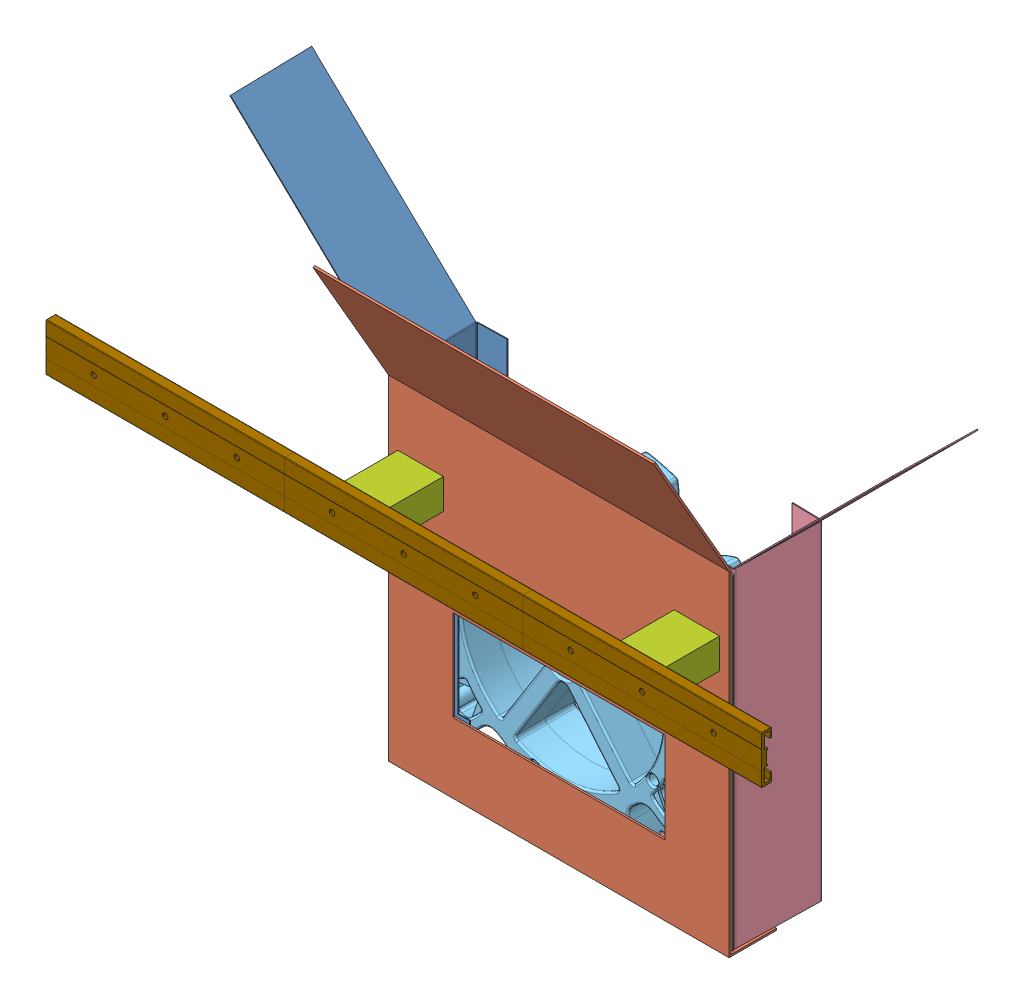
SolidWorks assembly Main Gear Asm, configuration Default. Lengths in mm.
Overall size (649.76 468.3 140.7).
37 component instances, 9 part files, 45 mates.
Components (placement in the parent):
- Right Side Gear Clamp-1: Right Side Gear Clamp [Default] at (-285.149 4.7752 -4.5915) x (-0.022934 0 -0.999737) z (0.999737 0 -0.022934) size (72.59 411.06 198.02)
- gear support back plate-1: gear support back plate [Default] at (0 1.6002 -1.6002) x (0 0 1) z (-1 0 0) size (102.99 390.99 285.75)
- Piano Hinge-1: Piano Hinge [Default] at (-286.5459 277.8252 -3.1875) x (0 -1 0) z (-0.999737 0 0.022934) size (273.05 1.59 10.45)
- Piano Hinge-2: Piano Hinge [Default] at (-286.5277 4.7752 -1.6002) x (0 1 0) z (-1 0 0) size (273.05 1.59 10.45)
- Piano Hinge-3: Piano Hinge [Default] at (0.7937 277.8252 -1.6002) x (0 -1 0) z (1 0 0) size (273.05 1.59 10.45)
- Piano Hinge-4: Piano Hinge [Default] at (0.81 4.7752 -3.1875) x (0 1 0) z (0.999791 0 0.020427) size (273.05 1.59 10.45)
- Left Side Gear Clamp-2: Left Side Gear Clamp [Default] at (0.8607 4.7752 -4.7362) x (0.020427 0 -0.999791) z (0.999791 0 0.020427) size (72.95 411.63 198.2)
- Gear Gampiece-1: Gear Gampiece [Default] at (-146.05 139.7 -30.6969) x (0.847389 -0.530972 0) z (0 0 1) size (282.2 275.37 50.81)
  - ip-3302 10T gear-1: ip-3302 10T gear [Default] at origin size (280.29 273.41 28.58)
  - ip-3302 10T gear-2: ip-3302 10T gear [Default] x (-0.999975 0.007024 0) z (0 0 -1) size (280.29 273.41 28.58)
  - am-1291 screw_90190A196-1: am-1291 screw_90190A196 [Default] at (-90.6774 0.3185 -5.969) x (-0.923728 -0.383049 0) z (0 0 -1) size (8.18 8.18 18.8)
  - am-1291 screw_90190A196-2: am-1291 screw_90190A196 [Default] at (-102.4824 75.0091 -4.3538) x (-0.923728 -0.383049 0) z (0 0 -1) size (8.18 8.18 18.8)
  - am-1291 screw_90190A196-3: am-1291 screw_90190A196 [Default] at (-126.9992 0.446 4.3538) size (8.18 8.18 18.8)
  - am-1291 screw_90190A196-4: am-1291 screw_90190A196 [Default] at (-73.1724 53.5565 5.969) size (8.18 8.18 18.8)
  - am-1291 screw_90190A196-5: am-1291 screw_90190A196 [Default] at (-27.718 86.3378 -5.969) x (-0.649749 0.760149 0) z (0 0 -1) size (8.18 8.18 18.8)
  - am-1291 screw_90190A196-6: am-1291 screw_90190A196 [Default] at (73.5468 53.0412 -5.969) x (0.522161 0.852847 0) z (0 0 -1) size (8.18 8.18 18.8)
  - am-1291 screw_90190A196-7: am-1291 screw_90190A196 [Default] at (73.1724 -53.5565 -5.969) x (0.972462 -0.233061 0) z (0 0 -1) size (8.18 8.18 18.8)
  - am-1291 screw_90190A196-8: am-1291 screw_90190A196 [Default] at (-28.3237 -86.141 -5.969) x (0.078854 -0.996886 0) z (0 0 -1) size (8.18 8.18 18.8)
  - am-1291 screw_90190A196-9: am-1291 screw_90190A196 [Default] at (39.6691 120.6456 -4.3538) x (-0.649749 0.760149 0) z (0 0 -1) size (8.18 8.18 18.8)
  - am-1291 screw_90190A196-10: am-1291 screw_90190A196 [Default] at (126.9992 -0.446 -4.3538) x (0.522161 0.852847 0) z (0 0 -1) size (8.18 8.18 18.8)
  - am-1291 screw_90190A196-11: am-1291 screw_90190A196 [Default] at (38.8207 -120.9213 -4.3538) x (0.972462 -0.233061 0) z (0 0 -1) size (8.18 8.18 18.8)
  - am-1291 screw_90190A196-12: am-1291 screw_90190A196 [Default] at (-103.0067 -74.2874 -4.3538) x (0.078854 -0.996886 0) z (0 0 -1) size (8.18 8.18 18.8)
  - am-1291 screw_90190A196-13: am-1291 screw_90190A196 [Default] at (-38.8207 120.9213 4.3538) x (0.309017 -0.951057 0) z (0 0 1) size (8.18 8.18 18.8)
  - am-1291 screw_90190A196-14: am-1291 screw_90190A196 [Default] at (103.0067 74.2874 4.3538) x (-0.809017 -0.587785 0) z (0 0 1) size (8.18 8.18 18.8)
  - am-1291 screw_90190A196-15: am-1291 screw_90190A196 [Default] at (102.4824 -75.0091 4.3538) x (-0.809017 0.587785 0) z (0 0 1) size (8.18 8.18 18.8)
  - am-1291 screw_90190A196-16: am-1291 screw_90190A196 [Default] at (-39.6691 -120.6456 4.3538) x (0.309017 0.951057 0) z (0 0 1) size (8.18 8.18 18.8)
  - am-1291 screw_90190A196-17: am-1291 screw_90190A196 [Default] at (28.3237 86.141 5.969) x (0.309017 -0.951057 0) z (0 0 1) size (8.18 8.18 18.8)
  - am-1291 screw_90190A196-18: am-1291 screw_90190A196 [Default] at (90.6774 -0.3185 5.969) x (-0.809017 -0.587785 0) z (0 0 1) size (8.18 8.18 18.8)
  - am-1291 screw_90190A196-19: am-1291 screw_90190A196 [Default] at (27.718 -86.3378 5.969) x (-0.809017 0.587785 0) z (0 0 1) size (8.18 8.18 18.8)
  - am-1291 screw_90190A196-20: am-1291 screw_90190A196 [Default] at (-73.5468 -53.0412 5.969) x (0.309017 0.951057 0) z (0 0 1) size (8.18 8.18 18.8)
- Slider Offset Block-1: Slider Offset Block [Default] at (-26.9875 217.0714 50.8) x (0 -1 0) z (1 0 0) size (25.4 50.8 38.1)
- Slider Offset Block-2: Slider Offset Block [Default] at (-258.7625 217.0714 50.8) x (0 1 0) z (-1 0 0) size (25.4 50.8 38.1)
- NW_02_40_2 carriage-1: NW_02_40_2 carriage [Default] at (-258.7625 217.0714 60.3) x (0 -1 0) z (0 0 -1) size (34 50 11.15)
- NW_02_40_2 carriage-2: NW_02_40_2 carriage [Default] at (-26.9875 217.0714 60.3) x (0 -1 0) z (0 0 -1) size (34 50 11.15)
- NS_01_40_200_1rail-1: NS_01_40_200_1rail [Default] at (-112.7625 217.0714 60.25) x (0 -1 0) z (0 0 -1) size (40 200 8.7)
- NS_01_40_200_1rail-2: NS_01_40_200_1rail [Default] at (-312.7625 217.0714 60.25) x (0 -1 0) z (0 0 -1) size (40 200 8.7)
- NS_01_40_200_1rail-3: NS_01_40_200_1rail [Default] at (87.2375 217.0714 60.25) x (0 -1 0) z (0 0 -1) size (40 200 8.7)
Mates (geometry in assembly coordinates):
- Concentric3: concentric anti-aligned: cylinder of Piano Hinge-1 through (-286.5277 4.7752 -2.394) axis (0 1 0) radius 0.7937; cylinder of Piano Hinge-2 through (-286.5277 277.8252 -2.394) axis (0 -1 0) radius 0.7937
- Coincident19: coincident aligned: plane of Piano Hinge-1 through (-286.5277 277.8252 -2.394) normal (0 1 0); plane of Piano Hinge-2 through (-286.5277 277.8252 -2.394) normal (0 1 0)
- Coincident20: coincident: plane of gear support back plate-1 through (-285.75 1.6002 -1.6002) normal (-1 0 0); line of Piano Hinge-2 through (-285.75 277.8252 -2.2352) axis (0 -1 0)
- Coincident21: coincident anti-aligned: plane of gear support back plate-1 through (-285.75 1.6002 -1.6002) normal (0 0 -1); plane of Piano Hinge-2 through (-286.5277 277.8252 -1.6002) normal (0 0 1)
- Distance2: distance = 3.175 mm anti-aligned: plane of Piano Hinge-2 through (-286.5277 4.7752 -2.394) normal (0 -1 0); plane of gear support back plate-1 through (-285.75 1.6002 -1.6002) normal (0 1 0)
- Coincident30: coincident aligned: plane of gear support back plate-1 through (-285.75 1.6002 0) normal (0 0 1); plane of assembly through (0 0 0) normal (0 0 1)
- Coincident31: coincident aligned: plane of gear support back plate-1 through (0 1.6002 -1.6002) normal (1 0 0); plane of assembly through (0 0 0) normal (1 0 0)
- Coincident32: coincident anti-aligned: plane of gear support back plate-1 through (-285.75 0 -1.6002) normal (0 -1 0); plane of assembly through (0 0 0) normal (0 1 0)
- Coincident33: coincident aligned: plane of Right Side Gear Clamp-1 through (-287.3858 4.7752 -74.4086) normal (0 -1 0); plane of Piano Hinge-1 through (-286.5277 4.7752 -2.394) normal (0 -1 0)
- Coincident34: coincident anti-aligned: plane of Right Side Gear Clamp-1 through (-285.1175 4.7752 -3.2203) normal (0.022934 0 0.999737); plane of Piano Hinge-1 through (-286.5459 4.7752 -3.1875) normal (-0.022934 0 -0.999737)
- Tangent1: tangent anti-aligned: plane of Right Side Gear Clamp-1 through (-287.3858 4.7752 -74.4086) normal (-0.999737 0 0.022934); cylinder of Piano Hinge-1 through (-286.5277 4.7752 -2.394) axis (0 1 0) radius 0.7937
- Concentric4: concentric anti-aligned: cylinder of Piano Hinge-3 through (0.7937 4.7752 -2.394) axis (0 1 0) radius 0.7937; cylinder of Piano Hinge-4 through (0.7937 277.8252 -2.394) axis (0 -1 0) radius 0.7937
- Coincident36: coincident aligned: plane of Piano Hinge-3 through (0.7937 277.8252 -2.394) normal (0 1 0); plane of Piano Hinge-4 through (0.7937 277.8252 -2.394) normal (0 1 0)
- Coincident37: coincident anti-aligned: plane of gear support back plate-1 through (-285.75 1.6002 -1.6002) normal (0 0 -1); plane of Piano Hinge-3 through (0.7937 4.7752 -1.6002) normal (0 0 1)
- Coincident38: coincident aligned: plane of Piano Hinge-2 through (-286.5277 4.7752 -2.394) normal (0 -1 0); plane of Piano Hinge-3 through (0.7937 4.7752 -2.394) normal (0 -1 0)
- Tangent2: tangent anti-aligned: plane of gear support back plate-1 through (0 1.6002 -1.6002) normal (1 0 0); cylinder of Piano Hinge-3 through (0.7937 4.7752 -2.394) axis (0 1 0) radius 0.7937
- Coincident40: coincident anti-aligned: plane of Piano Hinge-4 through (0.81 277.8252 -3.1875) normal (0.020427 0 -0.999791); plane of Left Side Gear Clamp-2 through (0.829 4.7752 -3.1871) normal (-0.020427 0 0.999791)
- Coincident41: coincident aligned: plane of Right Side Gear Clamp-1 through (-286.7824 4.7752 -75.7944) normal (0 -1 0); plane of Left Side Gear Clamp-2 through (1.4748 4.7752 -74.5883) normal (0 -1 0)
- Tangent4: tangent aligned: cylinder of Piano Hinge-3 through (0.7937 4.7752 -2.394) axis (0 1 0) radius 0.7937; plane of Left Side Gear Clamp-2 through (1.4748 4.7752 -74.5883) normal (-0.999791 0 -0.020427)
- Parallel7: parallel aligned: plane of gear support back plate-1 through (-285.75 1.6002 -1.6002) normal (0 0 -1); plane of Gear Gampiece-1/ip-3302 10T gear-2 through (-146.05 139.7 -56.0969) normal (0 0 -1)
- Distance3: distance = 146.05 mm: plane of gear support back plate-1 through (0 1.6002 -1.6002) normal (1 0 0)
- Coincident43: coincident: line of Right Side Gear Clamp-1 through (-222.2836 4.7752 -5.2969) axis (0 1 0); plane of Gear Gampiece-1/ip-3302 10T gear-1 through (-146.05 139.7 -5.2969) normal (0 0 1)
- Coincident49: coincident: line of Left Side Gear Clamp-2 through (-62.6411 280.8221 -5.2969) axis (0 -1 0); plane of Gear Gampiece-1/ip-3302 10T gear-1 through (-146.05 139.7 -5.2969) normal (0 0 1)
- Distance4: distance = 139.7 mm: plane of gear support back plate-1 through (-285.75 0 -1.6002) normal (0 -1 0)
- Coincident50: coincident anti-aligned: plane of gear support back plate-1 through (-285.75 1.6002 0) normal (0 0 1); plane of Slider Offset Block-1 through (-26.9875 217.0714 0) normal (0 0 -1)
- Coincident51: coincident anti-aligned: plane of gear support back plate-1 through (-285.75 1.6002 0) normal (0 0 1); plane of Slider Offset Block-2 through (-258.7625 217.0714 0) normal (0 0 -1)
- Width3: width anti-aligned: plane of Slider Offset Block-2 through (-239.7125 204.3714 0) normal (1 0 0); plane of Slider Offset Block-2 through (-277.8125 204.3714 0) normal (-1 0 0); plane of gear support back plate-1 through (-285.75 1.6002 -1.6002) normal (-1 0 0); plane of gear support back plate-1 through (-231.775 58.7502 -39.7002) normal (1 0 0)
- Coincident54: coincident aligned: plane of Slider Offset Block-1 through (-7.9375 229.7714 0) normal (0 1 0); plane of Slider Offset Block-2 through (-277.8125 229.7714 0) normal (0 1 0)
- Width4: width anti-aligned: plane of Slider Offset Block-1 through (-46.0375 229.7714 0) normal (-1 0 0); plane of Slider Offset Block-1 through (-7.9375 229.7714 0) normal (1 0 0); plane of gear support back plate-1 through (0 1.6002 -1.6002) normal (1 0 0); plane of gear support back plate-1 through (-53.975 58.7502 -39.7002) normal (-1 0 0)
- Distance6: distance = 50.8 mm: plane of Slider Offset Block-2 through (-277.8125 229.7714 0) normal (0 1 0); line of gear support back plate-1 through (-285.75 280.5714 0) axis (1 0 0)
- Concentric5: concentric aligned: cylinder of Slider Offset Block-2 through (-268.7625 217.0714 0) axis (0 0 1) radius 3.175; cylinder of NW_02_40_2 carriage-1 through (-268.7625 217.0714 48.8) axis (0 0 1) radius 3
- Concentric6: concentric aligned: cylinder of Slider Offset Block-2 through (-248.7625 217.0714 0) axis (0 0 1) radius 3.175; cylinder of NW_02_40_2 carriage-1 through (-248.7625 217.0714 48.8) axis (0 0 1) radius 3
- Coincident56: coincident anti-aligned: plane of Slider Offset Block-2 through (-258.7625 217.0714 50.8) normal (0 0 1); plane of NW_02_40_2 carriage-1 through (-238.7625 220.0714 50.8) normal (0 0 -1)
- Concentric7: concentric aligned: cylinder of Slider Offset Block-1 through (-36.9875 217.0714 0) axis (0 0 1) radius 3.175; cylinder of NW_02_40_2 carriage-2 through (-36.9875 217.0714 48.8) axis (0 0 1) radius 3
- Concentric8: concentric aligned: cylinder of Slider Offset Block-1 through (-16.9875 217.0714 0) axis (0 0 1) radius 3.175; cylinder of NW_02_40_2 carriage-2 through (-16.9875 217.0714 48.8) axis (0 0 1) radius 3
- Coincident58: coincident anti-aligned: plane of Slider Offset Block-1 through (-26.9875 217.0714 50.8) normal (0 0 1); plane of NW_02_40_2 carriage-2 through (-6.9875 220.0714 50.8) normal (0 0 -1)
- Coincident59: coincident anti-aligned: plane of NW_02_40_2 carriage-2 through (-51.9875 200.0714 57.45) normal (0 0 1); plane of NS_01_40_200_1rail-1 through (-112.7625 199.5714 57.45) normal (0 0 -1)
- Width5: width aligned: plane of NS_01_40_200_1rail-1 through (-112.7625 235.0714 56.95) normal (0 -1 0); plane of NS_01_40_200_1rail-1 through (-112.7625 199.0714 53.55) normal (0 1 0); plane of NW_02_40_2 carriage-2 through (-51.9875 200.0714 53.15) normal (0 -1 0); plane of NW_02_40_2 carriage-2 through (-51.9875 234.0714 57.45) normal (0 1 0)
- Coincident60: coincident anti-aligned: plane of NS_01_40_200_1rail-1 through (-312.7625 217.0714 56.5767) normal (-1 0 0); plane of NS_01_40_200_1rail-2 through (-312.7625 217.0714 56.5767) normal (1 0 0)
- Coincident61: coincident aligned: plane of NS_01_40_200_1rail-1 through (-112.7625 217.0714 60.25) normal (0 0 1); plane of NS_01_40_200_1rail-2 through (-312.7625 217.0714 60.25) normal (0 0 1)
- Coincident62: coincident aligned: plane of NS_01_40_200_1rail-1 through (-112.7625 237.0714 52.55) normal (0 1 0); plane of NS_01_40_200_1rail-2 through (-312.7625 237.0714 52.55) normal (0 1 0)
- Coincident64: coincident aligned: plane of NS_01_40_200_1rail-1 through (-112.7625 237.0714 52.55) normal (0 1 0); plane of NS_01_40_200_1rail-3 through (87.2375 237.0714 52.55) normal (0 1 0)
- Coincident65: coincident aligned: plane of NS_01_40_200_1rail-1 through (-112.7625 217.0714 60.25) normal (0 0 1); plane of NS_01_40_200_1rail-3 through (87.2375 217.0714 60.25) normal (0 0 1)
- Coincident66: coincident anti-aligned: plane of NS_01_40_200_1rail-1 through (-112.7625 217.0714 56.5767) normal (1 0 0); plane of NS_01_40_200_1rail-3 through (-112.7625 217.0714 56.5767) normal (-1 0 0)
- Distance7: distance = 234.95 mm aligned: plane of Slider Offset Block-2 through (-277.8125 204.3714 0) normal (-1 0 0); plane of NS_01_40_200_1rail-2 through (-512.7625 217.0714 56.5767) normal (-1 0 0)
